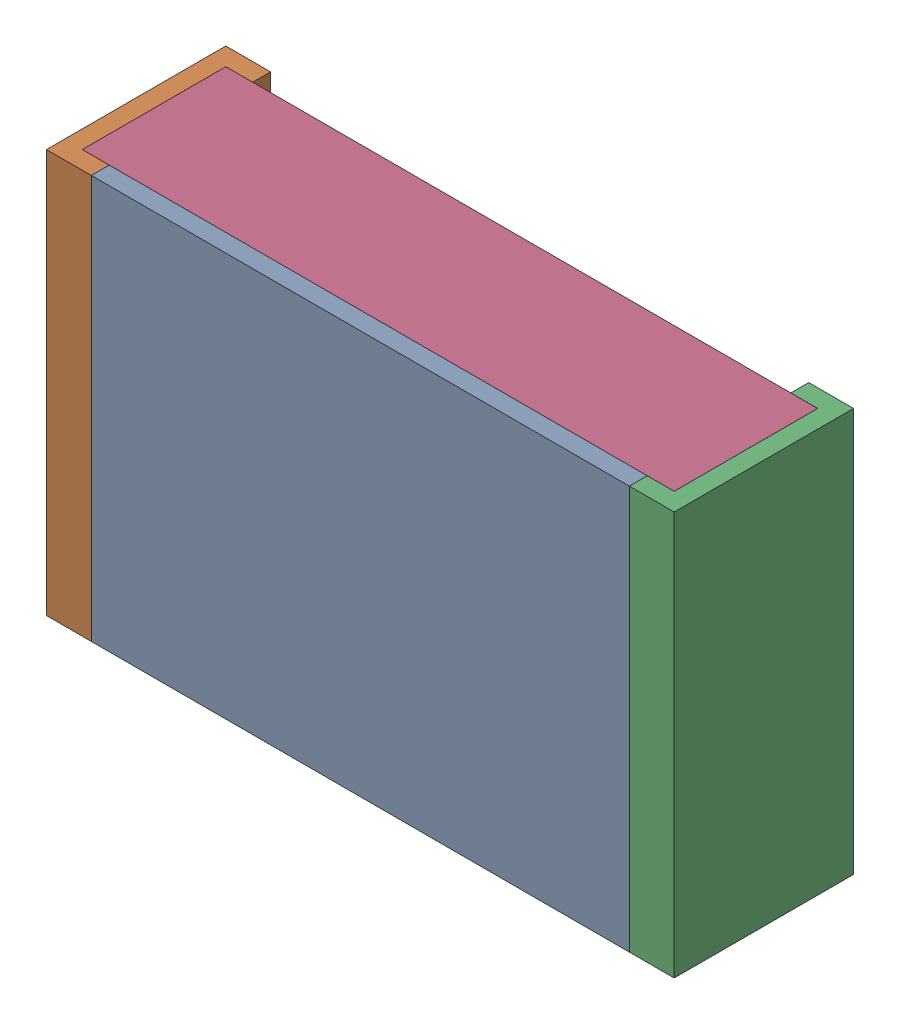
SolidWorks assembly RESC2012X06N.step-4, configuration По умолчанию. Lengths in mm.
Overall size (2.1 1.35 0.6).
4 component instances, 3 part files, 0 mates.
Components (placement in the parent):
- RESC2012X06N.step-Part-1-1: RESC2012X06N.step-Part-1 [По умолчанию] at (-0.9 -0.675 0.54) size (1.8 1.35 0.06)
- RESC2012X06N.step-Part-2-1: RESC2012X06N.step-Part-2 [По умолчанию] at (-1.05 -0.675 0) size (0.15 1.35 0.6)
- RESC2012X06N.step-Part-2-2: RESC2012X06N.step-Part-2 [По умолчанию] at (1.05 0.675 0) x (-1 0 0) z (0 0 1) size (0.15 1.35 0.6)
- RESC2012X06N.step-Part-3-1: RESC2012X06N.step-Part-3 [По умолчанию] at (-1.05 -0.675 0) size (1.98 1.35 0.48)
